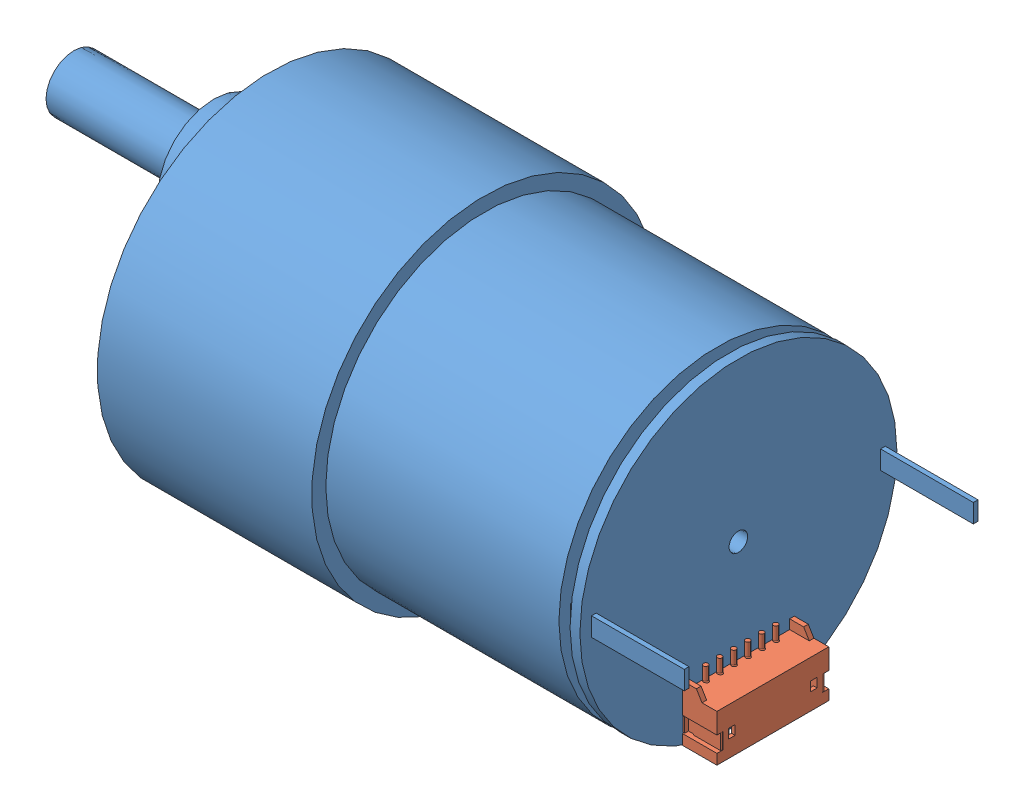
SolidWorks assembly CHR-GM37-545 (1-30), configuration Default. Lengths in mm.
Overall size (81.2 37 37).
2 component instances, 2 part files, 4 mates.
Components (placement in the parent):
- motor_CHR-GM37-3429K-ABHL-1: motor_CHR-GM37-3429K-ABHL [DC 12.0V 1000RMP-I10 without shaft] at origin size (81.2 37 37)
- S6B_ZR_SM4A_TF-1: S6B_ZR_SM4A_TF [Default] at (0 -3.106 0) x (1 0 0) z (0 0 -1) size (3.7 6.5 12)
Mates (geometry in assembly coordinates):
- 重合/共線/共點1: coincident anti-aligned: circle of motor_CHR-GM37-3429K-ABHL-1; plane of S6B_ZR_SM4A_TF-1 through (41.25 -9.906 -6) normal (-1 0 0)
- 平行1: parallel aligned: plane of motor_CHR-GM37-3429K-ABHL-1 through (51.2 -1 -15.75) normal (0 0 -1); plane of S6B_ZR_SM4A_TF-1 through (44.95 -15.906 -6) normal (0 0 -1)
- 重合/共線/共點2: coincident: point of motor_CHR-GM37-3429K-ABHL-1; point of S6B_ZR_SM4A_TF-1
- 重合/共線/共點3: coincident: circle of motor_CHR-GM37-3429K-ABHL-1; point of S6B_ZR_SM4A_TF-1
